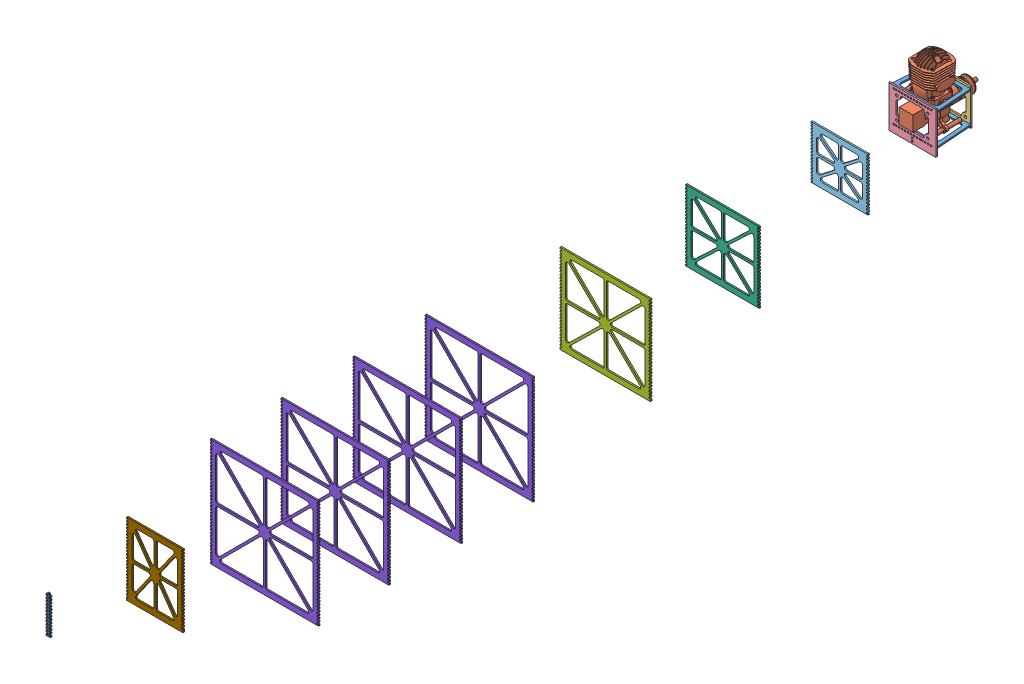
SolidWorks assembly asamblare carcasa_copy, configuration Default. Lengths in mm.
Overall size (300 377.28 2575.53).
14 component instances, 10 part files, 41 mates.
Components (placement in the parent):
- vertical_2_2-2: vertical_2_2 [Default] at (-71.6256 -334.7688 -268.2569) x (1 0 0) z (0 0 -1) size (130.8 4 108)
- vertical_2_2-3: vertical_2_2 [Default] at (-71.6256 -253.0188 -268.2569) x (-1 0 0) z (0 0 -1) size (130.8 4 108)
- JC-60 EVO-1: JC-60 EVO [По умолчанию] at (-71.6256 -291.7688 -398.7673) x (-1 0 0) z (0 0 -1) size (104 165.78 195)
- 1_Motor-1: 1_Motor [Default] at (-71.6256 -293.7688 -325.2326) x (-1 0 0) z (0 0 -1) size (128 101 4)
- 2-1: 2 [Default] at (-71.6256 -293.7688 -221.2326) x (-1 0 0) z (0 0 -1) size (130.8 115 4)
- 3-1: 3 [Default] at (-71.6256 -316.2688 -23.2326) size (157.7 146 4)
- 4-1: 4 [Default] at (-71.6256 -341.2688 301.7674) size (204 196 4)
- 5-1: 5 [Default] at (-71.6256 -366.2688 626.7674) size (250 246 4)
- 6-1: 6 [Default] at (-71.6256 -393.2688 976.7674) size (300 300 4)
- 6-2: 6 [Default] at (-71.6256 -393.2688 1176.7674) size (300 300 4)
- 6-3: 6 [Default] at (-71.6256 -393.2688 1376.7674) size (300 300 4)
- 6-4: 6 [Default] at (-71.6256 -393.2688 1572.7674) size (300 300 4)
- 7-1: 7 [Default] at (-71.6256 -343.2688 1876.7674) size (174 202.08 4)
- 8-1: 8 [Default] at (-69.6256 -273.4355 2176.7674) x (-1 0 0) z (0 -1 0) size (12 4 104)
Mates (geometry in assembly coordinates):
- Coincident17: coincident anti-aligned: plane of 2-1 through (-49.6256 -338.7688 -221.2326) normal (0 1 0); plane of vertical_2_2-2 through (-71.6256 -338.7688 -268.2569) normal (0 -1 0)
- Coincident19: coincident anti-aligned: plane of 2-1 through (-17.6256 -338.7688 -221.2326) normal (-1 0 0); plane of vertical_2_2-2 through (-17.6256 -334.7688 -225.2326) normal (1 0 0)
- Coincident20: coincident aligned: plane of 2-1 through (-71.6256 -293.7688 -221.2326) normal (0 0 1); plane of vertical_2_2-2 through (-21.6256 -334.7688 -221.2326) normal (0 0 1)
- Concentric2: concentric aligned: circle of 2-1; circle of 1_Motor-1
- Coincident37: coincident aligned: plane of vertical_2_2-2 through (-33.6256 -334.7688 -329.2326) normal (0 0 -1); plane of 1_Motor-1 through (-71.6256 -293.7688 -329.2326) normal (0 0 -1)
- Coincident38: coincident anti-aligned: plane of 2-1 through (-125.6256 -253.0188 -221.2326) normal (1 0 0); plane of vertical_2_2-3 through (-125.6256 -253.0188 -225.2326) normal (-1 0 0)
- Coincident39: coincident anti-aligned: plane of 2-1 through (-71.6256 -293.7688 -225.2326) normal (0 0 -1); plane of vertical_2_2-3 through (-6.2256 -249.0188 -225.2326) normal (0 0 1)
- Coincident41: coincident anti-aligned: plane of 2-1 through (-77.6256 -249.0188 -221.2326) normal (0 -1 0); plane of vertical_2_2-3 through (-71.6256 -249.0188 -268.2569) normal (0 1 0)
- Concentric4: concentric aligned: circle of 2-1; circle of JC-60 EVO-1
- Coincident42: coincident aligned: plane of 2-1 through (-71.6256 -243.2688 -225.2326) normal (0 1 0); plane of 3-1 through (-71.6256 -243.2688 -19.2326) normal (0 1 0)
- Parallel5: parallel: line of 2-1 through (-38.6256 -328.7688 -221.2326) axis (-1 0 0); plane of 3-1 through (-71.6256 -316.2688 -19.2326) normal (0 0 1)
- Distance3: distance = 1 mm anti-aligned: plane of 3-1 through (-68.6256 -316.2688 -19.2326) normal (1 0 0); plane of 2-1 through (-69.6256 -354.2688 -221.2326) normal (-1 0 0)
- Coincident52: coincident aligned: plane of 3-1 through (-71.6256 -243.2688 -19.2326) normal (0 1 0); plane of 4-1 through (-71.6256 -243.2688 305.7674) normal (0 1 0)
- Coincident53: coincident aligned: plane of 3-1 through (-74.6256 -316.2688 -19.2326) normal (-1 0 0); plane of 4-1 through (-74.6256 -341.2688 305.7674) normal (-1 0 0)
- Coincident56: coincident aligned: plane of 5-1 through (-71.6256 -243.2688 630.7674) normal (0 1 0); plane of 4-1 through (-71.6256 -243.2688 305.7674) normal (0 1 0)
- Coincident57: coincident aligned: plane of 5-1 through (-74.6256 -366.2688 630.7674) normal (-1 0 0); plane of 4-1 through (-74.6256 -341.2688 305.7674) normal (-1 0 0)
- Coincident60: coincident aligned: plane of 5-1 through (-71.6256 -243.2688 630.7674) normal (0 1 0); plane of 6-1 through (-71.6256 -243.2688 980.7674) normal (0 1 0)
- Coincident61: coincident aligned: plane of 5-1 through (-74.6256 -366.2688 630.7674) normal (-1 0 0); plane of 6-1 through (-74.6256 -393.2688 980.7674) normal (-1 0 0)
- Coincident62: coincident aligned: plane of 6-4 through (-71.6256 -243.2688 1576.7674) normal (0 1 0); plane of 6-3 through (-71.6256 -243.2688 1380.7674) normal (0 1 0)
- Coincident63: coincident aligned: plane of 6-4 through (-71.6256 -243.2688 1576.7674) normal (0 1 0); plane of 6-2 through (-71.6256 -243.2688 1180.7674) normal (0 1 0)
- Coincident64: coincident: plane of 6-4 through (-71.6256 -243.2688 1576.7674) normal (0 1 0); line of 6-1 through (-221.6256 -243.2688 976.7674) axis (1 0 0)
- Coincident65: coincident aligned: plane of 6-4 through (-71.6256 -243.2688 1576.7674) normal (0 1 0); plane of 6-1 through (-71.6256 -243.2688 980.7674) normal (0 1 0)
- Coincident66: coincident aligned: plane of 6-1 through (-74.6256 -393.2688 980.7674) normal (-1 0 0); plane of 6-2 through (-74.6256 -393.2688 1180.7674) normal (-1 0 0)
- Coincident67: coincident aligned: plane of 6-1 through (-74.6256 -393.2688 980.7674) normal (-1 0 0); plane of 6-3 through (-74.6256 -393.2688 1380.7674) normal (-1 0 0)
- Coincident68: coincident aligned: plane of 6-1 through (-74.6256 -393.2688 980.7674) normal (-1 0 0); plane of 6-4 through (-74.6256 -393.2688 1576.7674) normal (-1 0 0)
- Coincident69: coincident aligned: plane of 6-1 through (-74.6256 -393.2688 980.7674) normal (-1 0 0); plane of 5-1 through (-74.6256 -366.2688 630.7674) normal (-1 0 0)
- Distance8: distance = 196 mm anti-aligned: plane of 6-2 through (-71.6256 -393.2688 1176.7674) normal (0 0 -1); plane of 6-1 through (-71.6256 -393.2688 980.7674) normal (0 0 1)
- Distance9: distance = 196 mm anti-aligned: plane of 6-3 through (-71.6256 -393.2688 1376.7674) normal (0 0 -1); plane of 6-2 through (-71.6256 -393.2688 1180.7674) normal (0 0 1)
- Distance10: distance = 192 mm anti-aligned: plane of 6-3 through (-71.6256 -393.2688 1380.7674) normal (0 0 1); plane of 6-4 through (-71.6256 -393.2688 1572.7674) normal (0 0 -1)
- Coincident73: coincident aligned: plane of 6-4 through (-71.6256 -243.2688 1576.7674) normal (0 1 0); plane of 7-1 through (-71.6256 -243.2688 1880.7674) normal (0 1 0)
- Coincident74: coincident aligned: plane of 6-4 through (-74.6256 -393.2688 1576.7674) normal (-1 0 0); plane of 7-1 through (-74.6256 -343.2688 1880.7674) normal (-1 0 0)
- Distance11: distance = 300 mm anti-aligned: plane of 6-4 through (-71.6256 -393.2688 1576.7674) normal (0 0 1); plane of 7-1 through (-71.6256 -343.2688 1876.7674) normal (0 0 -1)
- Coincident83: coincident aligned: plane of 7-1 through (-71.6256 -243.2688 1880.7674) normal (0 1 0); plane of 8-1 through (-77.6256 -243.2688 2172.7674) normal (0 1 0)
- Distance14: distance = 1 mm aligned: plane of 8-1 through (-73.6256 -247.2688 2172.7674) normal (-1 0 0); plane of 7-1 through (-74.6256 -343.2688 1880.7674) normal (-1 0 0)
- Distance15: distance = 292 mm anti-aligned: plane of 7-1 through (-71.6256 -343.2688 1880.7674) normal (0 0 1); plane of 8-1 through (-69.6256 -273.4355 2172.7674) normal (0 0 -1)
- Distance16: distance = 198 mm anti-aligned: plane of 3-1 through (-71.6256 -316.2688 -23.2326) normal (0 0 -1); plane of 2-1 through (-71.6256 -293.7688 -221.2326) normal (0 0 1)
- Distance17: distance = 321 mm anti-aligned: plane of 4-1 through (-71.6256 -341.2688 301.7674) normal (0 0 -1); plane of 3-1 through (-71.6256 -316.2688 -19.2326) normal (0 0 1)
- Distance18: distance = 321 mm anti-aligned: plane of 5-1 through (-71.6256 -366.2688 626.7674) normal (0 0 -1); plane of 4-1 through (-71.6256 -341.2688 305.7674) normal (0 0 1)
- Distance19: distance = 346 mm anti-aligned: plane of 5-1 through (-71.6256 -366.2688 630.7674) normal (0 0 1); plane of 6-1 through (-71.6256 -393.2688 976.7674) normal (0 0 -1)
- Parallel7: parallel: line of vertical_2_2-2 through (-71.6256 -334.7688 -225.2326) axis (0 0 -1); plane of vertical_2_2-3 through (-71.6256 -249.0188 -268.2569) normal (0 1 0)
- Parallel8: parallel aligned: plane of JC-60 EVO-1 through (-90.6256 -270.7688 -203.7673) normal (0 1 0); plane of 2-1 through (-71.6256 -243.2688 -225.2326) normal (0 1 0)
